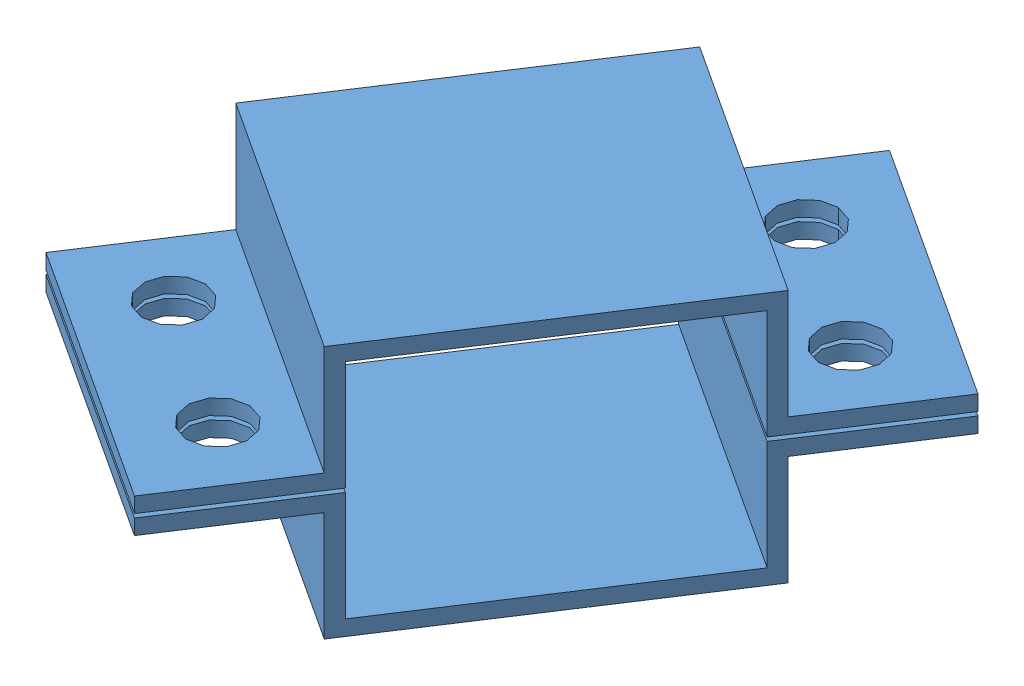
SolidWorks assembly Муфта, configuration По умолчанию. Lengths in mm.
Overall size (89.51 68.94 97.35).
2 component instances, 1 part files, 3 mates.
Components (placement in the parent):
- Скоба-1: Скоба [По умолчанию] at (18.0366 1 -0.5845) x (0.837169 0 0.546944) z (-0.546944 0 0.837169) size (47 57.49 81)
- Скоба-2: Скоба [По умолчанию] at (51.5234 0.5 21.2933) x (-0.837169 0 -0.546944) z (-0.546944 0 0.837169) size (47 57.49 81)
Mates (geometry in assembly coordinates):
- Расстояние1: distance = 0.5 mm anti-aligned: plane of Скоба-2 through (-9.9748 0.5 29.4922) normal (0 1 0); plane of Скоба-1 through (35.2323 1 59.0272) normal (0 -1 0)
- Концентричный1: concentric anti-aligned: cylinder of Скоба-1 through (10 11 30) axis (0 -1 0) radius 4; cylinder of Скоба-2 through (10 -9.5 30) axis (0 1 0) radius 4
- Концентричный2: concentric anti-aligned: cylinder of Скоба-1 through (59.56 11 -9.2913) axis (0 -1 0) radius 4; cylinder of Скоба-2 through (59.56 -9.5 -9.2913) axis (0 1 0) radius 4
